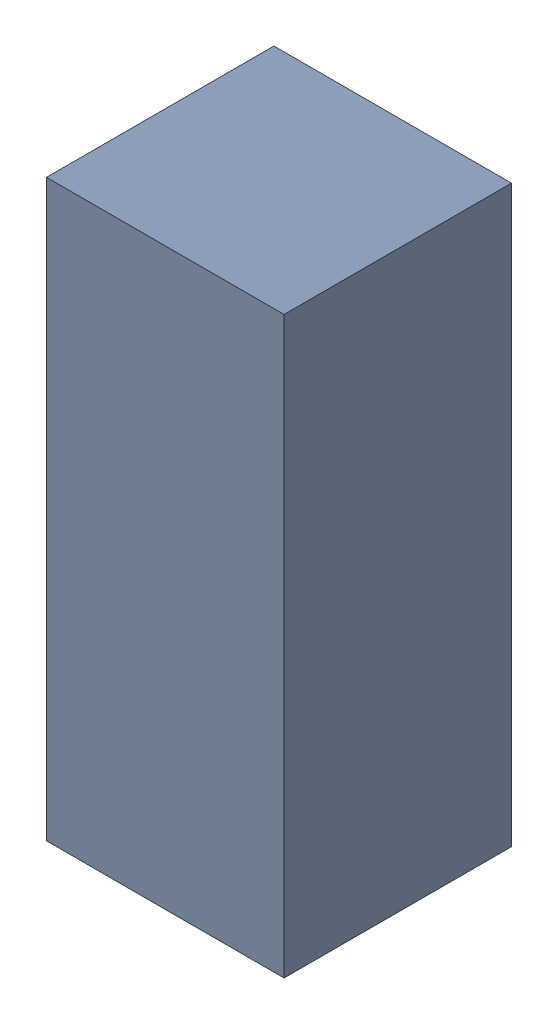
SolidWorks assembly U6, configuration Default. Lengths in mm.
Overall size (1.19 2.89 1.14).
2 component instances, 1 part files, 0 mates.
Components (placement in the parent):
- 804394704-1: 804394704 [Default] at (18.4081 62.0938 -1.5545) size (1.19 2.89 1.14)
  - Extruded (15)-1: Extruded (15) [Default] at origin size (1.19 2.89 1.14)
